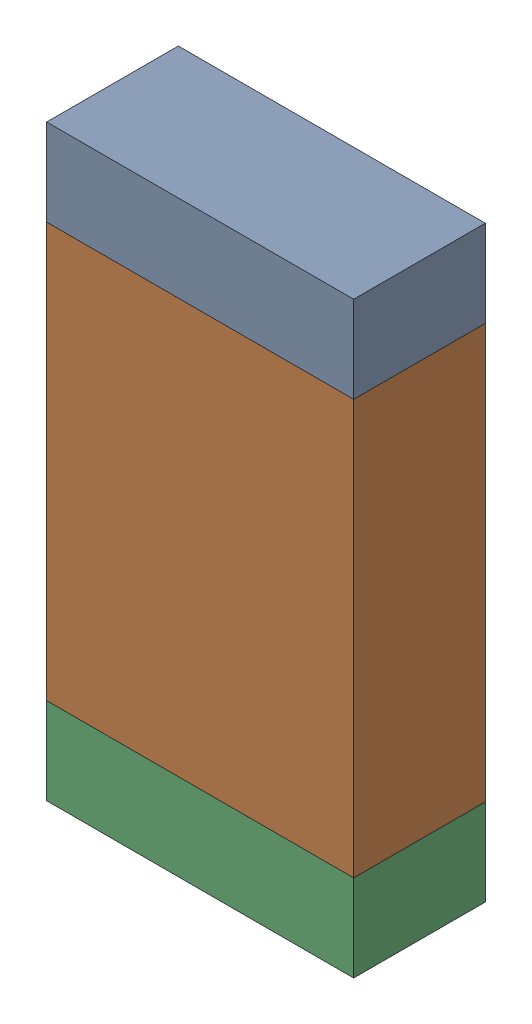
SolidWorks assembly R02-1, configuration Default. Lengths in mm.
Overall size (1.75 3.35 0.75).
6 component instances, 2 part files, 0 mates.
Components (placement in the parent):
- 959207032-1-1: 959207032-1 [Default] at (128.1431 81.3844 0) size (1.75 0.49 0.75)
  - Extruded-35-1: Extruded-35 [Default] at origin size (1.75 0.49 0.75)
- 959207168-1-1: 959207168-1 [Default] at (128.1431 79.9569 0) size (1.75 2.36 0.75)
  - Extruded-36-1: Extruded-36 [Default] at origin size (1.75 2.36 0.75)
- 959207032-1-2: 959207032-1 [Default] at (128.1431 78.5294 0) size (1.75 0.49 0.75)
  - Extruded-35-1: Extruded-35 [Default] at origin size (1.75 0.49 0.75)
